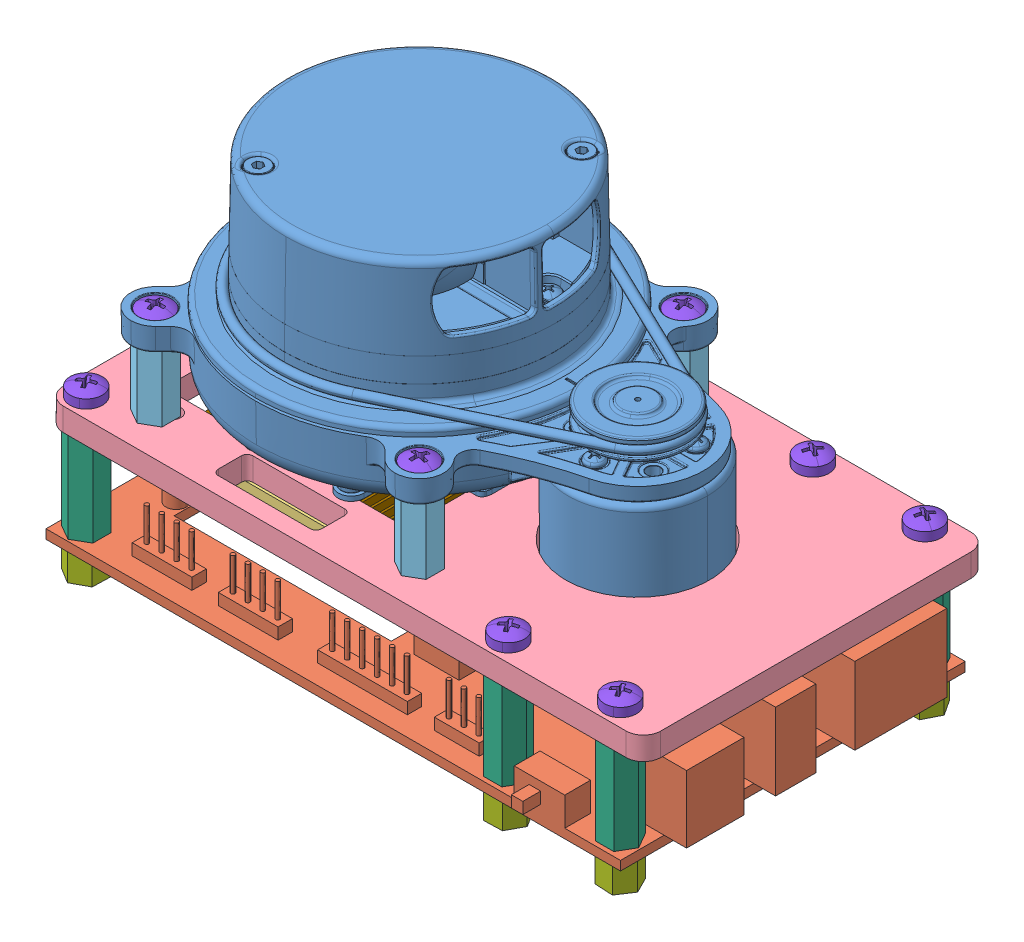
SolidWorks assembly SLAMTEC MAPPER M1M1, configuration 預設. Lengths in mm.
Overall size (166.71 77.4 122.31).
37 component instances, 10 part files, 0 mates.
Components (placement in the parent):
- SLAMTEC MAPPER M1M1(2)^SLAMTEC MAPPER M1M1-1: SLAMTEC MAPPER M1M1(2)^SLAMTEC MAPPER M1M1 [預設] at origin size (119.02 77.4 122.31) (virtual)
  - LDS-15BDM-1^SLAMTEC MAPPER M1M1(2)_SLAMTEC MAPPER M1M1-1: LDS-15BDM-1^SLAMTEC MAPPER M1M1(2)_SLAMTEC MAPPER M1M1 [預設] at (-5 0 0) size (106.4 60.52 122.31) (virtual)
  - breakout1.0^SLAMTEC MAPPER M1M1(2)_SLAMTEC MAPPER M1M1-1: breakout1.0^SLAMTEC MAPPER M1M1(2)_SLAMTEC MAPPER M1M1 [預設] at (10 -53.6 0) x (-1 0 0) z (0 1 0) size (103.91 64.41 15.01) (virtual)
  - 3308^SLAMTEC MAPPER M1M1(2)_SLAMTEC MAPPER M1M1-1: 3308^SLAMTEC MAPPER M1M1(2)_SLAMTEC MAPPER M1M1 [預設] at (-10.2 -47 2.4499) x (0 1 0) z (1 0 0) size (10.01 30.01 51.01) (virtual)
  - MP1-捚親薯脯啣^SLAMTEC MAPPER M1M1(2)_SLAMTEC MAPPER M1M1-1: MP1-捚親薯脯啣^SLAMTEC MAPPER M1M1(2)_SLAMTEC MAPPER M1M1 [預設] at (10 -32 0) x (0 0 -1) z (0 -1 0) size (60.13 104.13 4.07) (virtual)
  - M3℅12攝韓鞠褒邧籵蹟翐^SLAMTEC MAPPER M1M1(2)_SLAMTEC MAPPER M1M1-1: M3℅12攝韓鞠褒邧籵蹟翐^SLAMTEC MAPPER M1M1(2)_SLAMTEC MAPPER M1M1 [預設] at (-27.981 -32 22.981) x (1 0 0) z (0 1 0) size (5.51 6.36 12.01) (virtual)
  - M3℅12攝韓鞠褒邧籵蹟翐^SLAMTEC MAPPER M1M1(2)_SLAMTEC MAPPER M1M1-2: M3℅12攝韓鞠褒邧籵蹟翐^SLAMTEC MAPPER M1M1(2)_SLAMTEC MAPPER M1M1 [預設] at (17.981 -20 22.981) x (-1 0 0) z (0 -1 0) size (5.51 6.36 12.01) (virtual)
  - M3℅12攝韓鞠褒邧籵蹟翐^SLAMTEC MAPPER M1M1(2)_SLAMTEC MAPPER M1M1-3: M3℅12攝韓鞠褒邧籵蹟翐^SLAMTEC MAPPER M1M1(2)_SLAMTEC MAPPER M1M1 [預設] at (-27.981 -20 -22.981) x (1 0 0) z (0 -1 0) size (5.51 6.36 12.01) (virtual)
  - M3℅12攝韓鞠褒邧籵蹟翐^SLAMTEC MAPPER M1M1(2)_SLAMTEC MAPPER M1M1-4: M3℅12攝韓鞠褒邧籵蹟翐^SLAMTEC MAPPER M1M1(2)_SLAMTEC MAPPER M1M1 [預設] at (17.981 -32 -22.981) x (-1 0 0) z (0 1 0) size (5.51 6.36 12.01) (virtual)
  - M3℅30攝韓鞠褒邧籵蹟翐^SLAMTEC MAPPER M1M1(2)_SLAMTEC MAPPER M1M1-1: M3℅30攝韓鞠褒邧籵蹟翐^SLAMTEC MAPPER M1M1(2)_SLAMTEC MAPPER M1M1 [預設] at (-36.5 -52 26.5) x (1 0 0) z (0 1 0) size (5.51 6.36 16.01) (virtual)
  - M3℅30攝韓鞠褒邧籵蹟翐^SLAMTEC MAPPER M1M1(2)_SLAMTEC MAPPER M1M1-2: M3℅30攝韓鞠褒邧籵蹟翐^SLAMTEC MAPPER M1M1(2)_SLAMTEC MAPPER M1M1 [預設] at (37 -52 26.5) x (-0.866025 0 0.5) z (0 1 0) size (5.51 6.36 16.01) (virtual)
  - M3℅30攝韓鞠褒邧籵蹟翐^SLAMTEC MAPPER M1M1(2)_SLAMTEC MAPPER M1M1-3: M3℅30攝韓鞠褒邧籵蹟翐^SLAMTEC MAPPER M1M1(2)_SLAMTEC MAPPER M1M1 [預設] at (56.5 -52 26.5) x (-0.866025 0 0.5) z (0 1 0) size (5.51 6.36 16.01) (virtual)
  - M3℅30攝韓鞠褒邧籵蹟翐^SLAMTEC MAPPER M1M1(2)_SLAMTEC MAPPER M1M1-4: M3℅30攝韓鞠褒邧籵蹟翐^SLAMTEC MAPPER M1M1(2)_SLAMTEC MAPPER M1M1 [預設] at (-36.5 -36 -26.5) x (1 0 0) z (0 -1 0) size (5.51 6.36 16.01) (virtual)
  - M3℅30攝韓鞠褒邧籵蹟翐^SLAMTEC MAPPER M1M1(2)_SLAMTEC MAPPER M1M1-5: M3℅30攝韓鞠褒邧籵蹟翐^SLAMTEC MAPPER M1M1(2)_SLAMTEC MAPPER M1M1 [預設] at (37 -36 -26.5) x (-0.866025 0 -0.5) z (0 -1 0) size (5.51 6.36 16.01) (virtual)
  - M3℅30攝韓鞠褒邧籵蹟翐^SLAMTEC MAPPER M1M1(2)_SLAMTEC MAPPER M1M1-6: M3℅30攝韓鞠褒邧籵蹟翐^SLAMTEC MAPPER M1M1(2)_SLAMTEC MAPPER M1M1 [預設] at (56.5 -36 -26.5) x (-0.866025 0 -0.5) z (0 -1 0) size (5.51 6.36 16.01) (virtual)
  - M3℅5+6攝韓鞠褒等籵蹟翐^SLAMTEC MAPPER M1M1(2)_SLAMTEC MAPPER M1M1-1: M3℅5+6攝韓鞠褒等籵蹟翐^SLAMTEC MAPPER M1M1(2)_SLAMTEC MAPPER M1M1 [預設] at (-36.5 -53.6 26.5) x (-0.999608 0 -0.027987) z (0 -1 0) size (5.51 6.36 11.01) (virtual)
  - M3℅5+6攝韓鞠褒等籵蹟翐^SLAMTEC MAPPER M1M1(2)_SLAMTEC MAPPER M1M1-2: M3℅5+6攝韓鞠褒等籵蹟翐^SLAMTEC MAPPER M1M1(2)_SLAMTEC MAPPER M1M1 [預設] at (37 -53.6 26.5) x (-0.0294 0 -0.999568) z (0 -1 0) size (5.51 6.36 11.01) (virtual)
  - M3℅5+6攝韓鞠褒等籵蹟翐^SLAMTEC MAPPER M1M1(2)_SLAMTEC MAPPER M1M1-3: M3℅5+6攝韓鞠褒等籵蹟翐^SLAMTEC MAPPER M1M1(2)_SLAMTEC MAPPER M1M1 [預設] at (56.5 -53.6 26.5) x (-0.835498 0 -0.549494) z (0 -1 0) size (5.51 6.36 11.01) (virtual)
  - M3℅5+6攝韓鞠褒等籵蹟翐^SLAMTEC MAPPER M1M1(2)_SLAMTEC MAPPER M1M1-4: M3℅5+6攝韓鞠褒等籵蹟翐^SLAMTEC MAPPER M1M1(2)_SLAMTEC MAPPER M1M1 [預設] at (-36.5 -53.6 -26.5) x (0.999608 0 -0.027987) z (0 -1 0) size (5.51 6.36 11.01) (virtual)
  - M3℅5+6攝韓鞠褒等籵蹟翐^SLAMTEC MAPPER M1M1(2)_SLAMTEC MAPPER M1M1-5: M3℅5+6攝韓鞠褒等籵蹟翐^SLAMTEC MAPPER M1M1(2)_SLAMTEC MAPPER M1M1 [預設] at (37 -53.6 -26.5) x (0.0294 0 -0.999568) z (0 -1 0) size (5.51 6.36 11.01) (virtual)
  - M3℅5+6攝韓鞠褒等籵蹟翐^SLAMTEC MAPPER M1M1(2)_SLAMTEC MAPPER M1M1-6: M3℅5+6攝韓鞠褒等籵蹟翐^SLAMTEC MAPPER M1M1(2)_SLAMTEC MAPPER M1M1 [預設] at (56.5 -53.6 -26.5) x (0.835498 0 -0.549494) z (0 -1 0) size (5.51 6.36 11.01) (virtual)
  - cross recessed pan head screws gb_GB_CROSS_SCREWS_TYPE1 M3X8-8  H type-S^SLAMTEC MAPPER M1M1(2)_SLAMTEC MAPPER M1M1-1: cross recessed pan head screws gb_GB_CROSS_SCREWS_TYPE1 M3X8-8  H type-S^SLAMTEC MAPPER M1M1(2)_SLAMTEC MAPPER M1M1 [預設] at (-27.981 -15.4 22.981) x (0 -1 0) z (0.165081 0 0.98628) size (10.41 5.61 5.61) (virtual)
  - cross recessed pan head screws gb_GB_CROSS_SCREWS_TYPE1 M3X8-8  H type-S^SLAMTEC MAPPER M1M1(2)_SLAMTEC MAPPER M1M1-2: cross recessed pan head screws gb_GB_CROSS_SCREWS_TYPE1 M3X8-8  H type-S^SLAMTEC MAPPER M1M1(2)_SLAMTEC MAPPER M1M1 [預設] at (17.981 -15.4 22.981) x (0 -1 0) z (0.165081 0 -0.98628) size (10.41 5.61 5.61) (virtual)
  - cross recessed pan head screws gb_GB_CROSS_SCREWS_TYPE1 M3X8-8  H type-S^SLAMTEC MAPPER M1M1(2)_SLAMTEC MAPPER M1M1-3: cross recessed pan head screws gb_GB_CROSS_SCREWS_TYPE1 M3X8-8  H type-S^SLAMTEC MAPPER M1M1(2)_SLAMTEC MAPPER M1M1 [預設] at (-27.981 -15.4 -22.981) x (0 -1 0) z (-0.165081 0 0.98628) size (10.41 5.61 5.61) (virtual)
  - cross recessed pan head screws gb_GB_CROSS_SCREWS_TYPE1 M3X8-8  H type-S^SLAMTEC MAPPER M1M1(2)_SLAMTEC MAPPER M1M1-4: cross recessed pan head screws gb_GB_CROSS_SCREWS_TYPE1 M3X8-8  H type-S^SLAMTEC MAPPER M1M1(2)_SLAMTEC MAPPER M1M1 [預設] at (17.981 -15.4 -22.981) x (0 -1 0) z (-0.165081 0 -0.98628) size (10.41 5.61 5.61) (virtual)
  - cross recessed pan head screws gb_GB_CROSS_SCREWS_TYPE1 M3X8-8  H type-S^SLAMTEC MAPPER M1M1(2)_SLAMTEC MAPPER M1M1-5: cross recessed pan head screws gb_GB_CROSS_SCREWS_TYPE1 M3X8-8  H type-S^SLAMTEC MAPPER M1M1(2)_SLAMTEC MAPPER M1M1 [預設] at (-27.981 -38.4 22.981) x (0 1 0) z (-0.677641 0 0.735393) size (10.41 5.61 5.61) (virtual)
  - cross recessed pan head screws gb_GB_CROSS_SCREWS_TYPE1 M3X8-8  H type-S^SLAMTEC MAPPER M1M1(2)_SLAMTEC MAPPER M1M1-6: cross recessed pan head screws gb_GB_CROSS_SCREWS_TYPE1 M3X8-8  H type-S^SLAMTEC MAPPER M1M1(2)_SLAMTEC MAPPER M1M1 [預設] at (17.981 -38.4 22.981) x (0 1 0) z (-0.677641 0 -0.735393) size (10.41 5.61 5.61) (virtual)
  - cross recessed pan head screws gb_GB_CROSS_SCREWS_TYPE1 M3X8-8  H type-S^SLAMTEC MAPPER M1M1(2)_SLAMTEC MAPPER M1M1-7: cross recessed pan head screws gb_GB_CROSS_SCREWS_TYPE1 M3X8-8  H type-S^SLAMTEC MAPPER M1M1(2)_SLAMTEC MAPPER M1M1 [預設] at (-27.981 -38.4 -22.981) x (0 1 0) z (0.677641 0 0.735393) size (10.41 5.61 5.61) (virtual)
  - cross recessed pan head screws gb_GB_CROSS_SCREWS_TYPE1 M3X8-8  H type-S^SLAMTEC MAPPER M1M1(2)_SLAMTEC MAPPER M1M1-8: cross recessed pan head screws gb_GB_CROSS_SCREWS_TYPE1 M3X8-8  H type-S^SLAMTEC MAPPER M1M1(2)_SLAMTEC MAPPER M1M1 [預設] at (17.981 -38.4 -22.981) x (0 1 0) z (0.677641 0 -0.735393) size (10.41 5.61 5.61) (virtual)
  - cross recessed pan head screws gb_GB_CROSS_SCREWS_TYPE1 M3X8-8  H type-S^SLAMTEC MAPPER M1M1(2)_SLAMTEC MAPPER M1M1-9: cross recessed pan head screws gb_GB_CROSS_SCREWS_TYPE1 M3X8-8  H type-S^SLAMTEC MAPPER M1M1(2)_SLAMTEC MAPPER M1M1 [預設] at (-36.5 -29.6 26.5) x (0 -1 0) z (0.476171 0 0.879353) size (10.41 5.61 5.61) (virtual)
  - cross recessed pan head screws gb_GB_CROSS_SCREWS_TYPE1 M3X8-8  H type-S^SLAMTEC MAPPER M1M1(2)_SLAMTEC MAPPER M1M1-10: cross recessed pan head screws gb_GB_CROSS_SCREWS_TYPE1 M3X8-8  H type-S^SLAMTEC MAPPER M1M1(2)_SLAMTEC MAPPER M1M1 [預設] at (37 -29.6 26.5) x (0 -1 0) z (0.504487 0 0.863419) size (10.41 5.61 5.61) (virtual)
  - cross recessed pan head screws gb_GB_CROSS_SCREWS_TYPE1 M3X8-8  H type-S^SLAMTEC MAPPER M1M1(2)_SLAMTEC MAPPER M1M1-11: cross recessed pan head screws gb_GB_CROSS_SCREWS_TYPE1 M3X8-8  H type-S^SLAMTEC MAPPER M1M1(2)_SLAMTEC MAPPER M1M1 [預設] at (56.5 -29.6 26.5) x (0 -1 0) z (0.462148 0 0.886803) size (10.41 5.61 5.61) (virtual)
  - cross recessed pan head screws gb_GB_CROSS_SCREWS_TYPE1 M3X8-8  H type-S^SLAMTEC MAPPER M1M1(2)_SLAMTEC MAPPER M1M1-12: cross recessed pan head screws gb_GB_CROSS_SCREWS_TYPE1 M3X8-8  H type-S^SLAMTEC MAPPER M1M1(2)_SLAMTEC MAPPER M1M1 [預設] at (-36.5 -29.6 -26.5) x (0 -1 0) z (-0.476171 0 0.879353) size (10.41 5.61 5.61) (virtual)
  - cross recessed pan head screws gb_GB_CROSS_SCREWS_TYPE1 M3X8-8  H type-S^SLAMTEC MAPPER M1M1(2)_SLAMTEC MAPPER M1M1-13: cross recessed pan head screws gb_GB_CROSS_SCREWS_TYPE1 M3X8-8  H type-S^SLAMTEC MAPPER M1M1(2)_SLAMTEC MAPPER M1M1 [預設] at (37 -29.6 -26.5) x (0 -1 0) z (-0.504487 0 0.863419) size (10.41 5.61 5.61) (virtual)
  - cross recessed pan head screws gb_GB_CROSS_SCREWS_TYPE1 M3X8-8  H type-S^SLAMTEC MAPPER M1M1(2)_SLAMTEC MAPPER M1M1-14: cross recessed pan head screws gb_GB_CROSS_SCREWS_TYPE1 M3X8-8  H type-S^SLAMTEC MAPPER M1M1(2)_SLAMTEC MAPPER M1M1 [預設] at (56.5 -29.6 -26.5) x (0 -1 0) z (-0.462148 0 0.886803) size (10.41 5.61 5.61) (virtual)
  - 瑞圮^SLAMTEC MAPPER M1M1(2)_SLAMTEC MAPPER M1M1-1: 瑞圮^SLAMTEC MAPPER M1M1(2)_SLAMTEC MAPPER M1M1 [預設] at (-9.95 -25.9 2.4499) x (1 0 0) z (0 -1 0) size (37.61 30.01 5.01) (virtual)
  - User Library-JST SHR-06-V-S-B (1MM PITCH WIRE-TO-BOARD, RECEPTACLE)^SLAMTEC MAPPER M1M1(2)_SLAMTEC MAPPER M1M1-1: User Library-JST SHR-06-V-S-B (1MM PITCH WIRE-TO-BOARD, RECEPTACLE)^SLAMTEC MAPPER M1M1(2)_SLAMTEC MAPPER M1M1 [預設] at (-4.855 -30 16.404) x (-1 0 0) z (0 1 0) size (9.01 5.01 2.87) (virtual)
